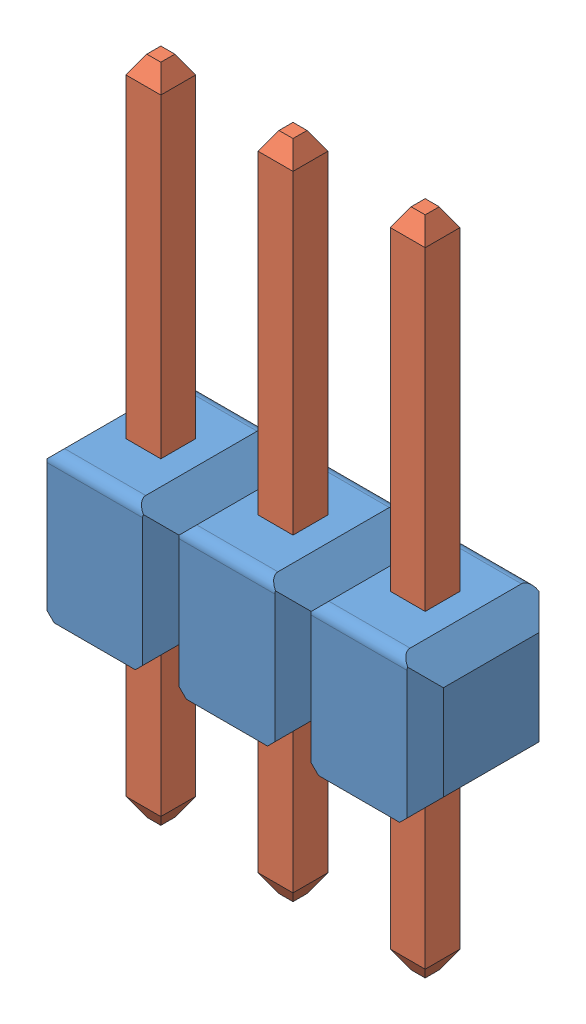
SolidWorks assembly User Library-1x3 TH Pitch 2_54mm, configuration Default. Lengths in mm.
Overall size (7.62 12.7 2.54).
4 component instances, 2 part files, 0 mates.
Components (placement in the parent):
- User Library-1x3 TH Pitch 2_54mm_holder-1: User Library-1x3 TH Pitch 2_54mm_holder [Default] at (0 1.4 0) size (7.62 2.8 2.54)
- User Library-1x3 TH Pitch 2_54mm_pin-1: User Library-1x3 TH Pitch 2_54mm_pin [Default] at (-2.56 -3.5 -0.02) size (0.67 12.7 0.67)
- User Library-1x3 TH Pitch 2_54mm_pin-2: User Library-1x3 TH Pitch 2_54mm_pin [Default] at (-0.02 -3.5 -0.02) size (0.67 12.7 0.67)
- User Library-1x3 TH Pitch 2_54mm_pin-3: User Library-1x3 TH Pitch 2_54mm_pin [Default] at (2.52 -3.5 -0.02) size (0.67 12.7 0.67)
